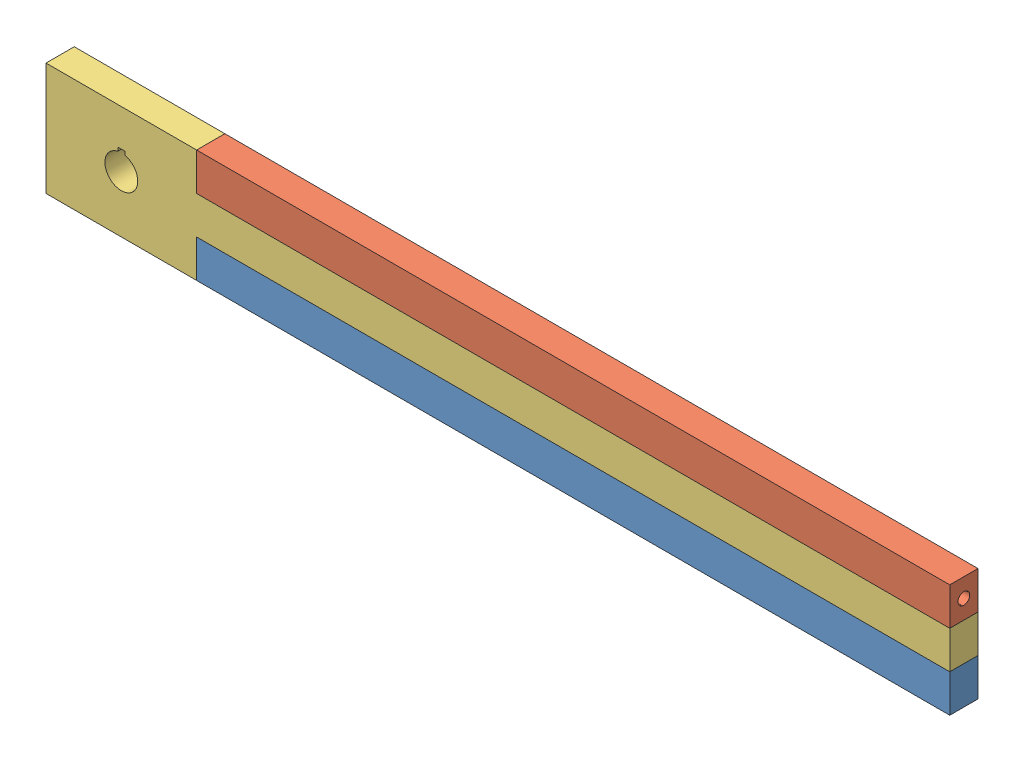
SolidWorks assembly Arm Assembly, configuration Default. Lengths in mm.
Overall size (609.6 76.2 19.05).
3 component instances, 3 part files, 5 mates.
Components (placement in the parent):
- Connector Arm-1: Connector Arm [Default] at (-266.8185 -20.4571 21.5592) size (508 25.4 19.05)
- Ankle Arm-1: Ankle Arm [Default] at (-266.8185 30.3429 21.5592) size (508 25.4 19.05)
- Gearbox Arm-1: Gearbox Arm [Default] at (-303.2022 32.4024 2.5092) size (609.6 76.2 19.05)
Mates (geometry in assembly coordinates):
- Coincident5: coincident anti-aligned: plane of Ankle Arm-1 through (-266.8185 30.3429 2.5092) normal (-1 0 0); plane of Gearbox Arm-1 through (-266.8185 30.3429 21.5592) normal (1 0 0)
- Coincident6: coincident anti-aligned: line of Ankle Arm-1 through (-266.8185 55.7429 21.5592) axis (0 -1 0); line of Gearbox Arm-1 through (-266.8185 30.3429 21.5592) axis (0 1 0)
- Coincident7: coincident anti-aligned: plane of Ankle Arm-1 through (-266.8185 30.3429 2.5092) normal (0 -1 0); plane of Gearbox Arm-1 through (241.1815 30.3429 21.5592) normal (0 1 0)
- Coincident8: coincident anti-aligned: line of Connector Arm-1 through (-266.8185 4.9429 2.5092) axis (0 0 1); line of Gearbox Arm-1 through (-266.8185 4.9429 21.5592) axis (0 0 -1)
- Coincident9: coincident anti-aligned: line of Connector Arm-1 through (-266.8185 4.9429 2.5092) axis (0 -1 0); line of Gearbox Arm-1 through (-266.8185 -20.4571 2.5092) axis (0 1 0)
